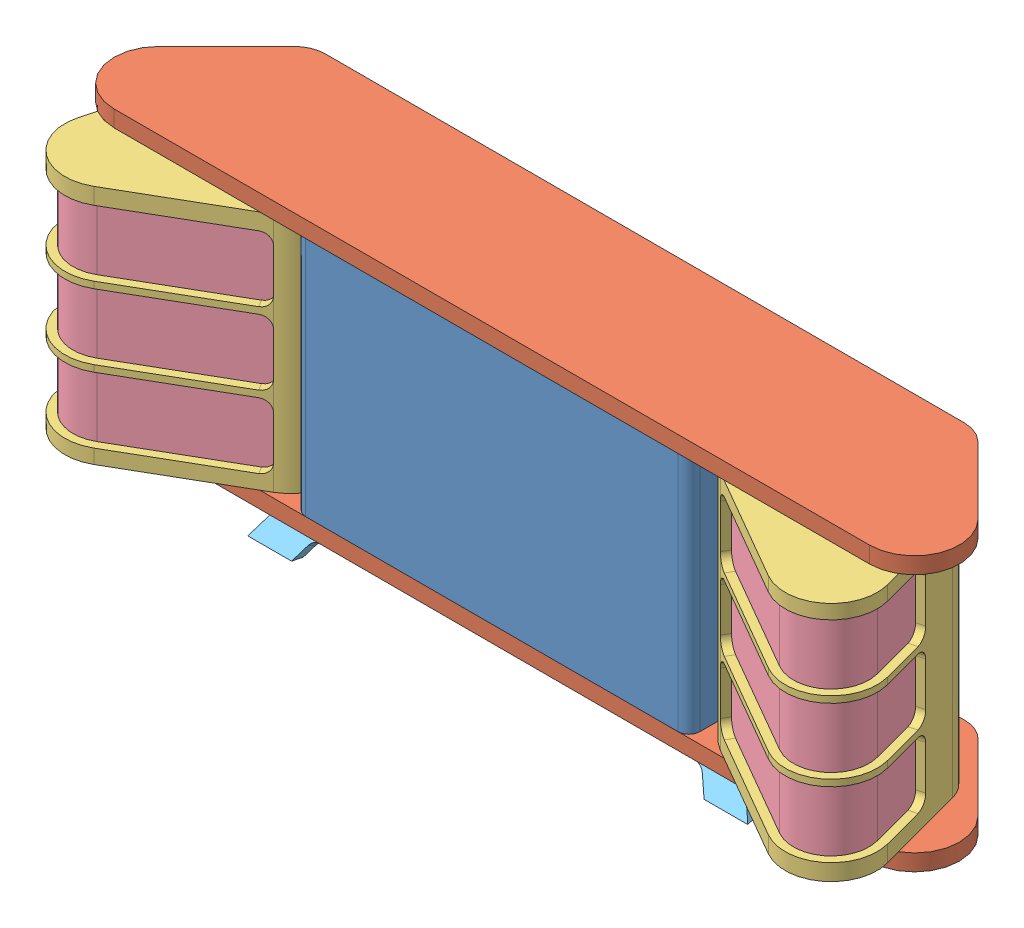
SolidWorks assembly Speakers installed, configuration Default. Lengths in mm.
Overall size (2104.56 725.08 567.1).
9 component instances, 5 part files, 24 mates.
Components (placement in the parent):
- Middle-1: Middle [Default] at (409.9999 227.4076 645.5134) size (914.4 558.8 355.6)
- top bottom-1: top bottom [Default] at (352.252 227.4076 660.7734) x (-1 0 0) z (0 0 1) size (1960.6 38.1 355.6)
- top bottom-2: top bottom [Default] at (467.7478 786.2076 660.7734) size (1960.6 38.1 355.6)
- speaker-1: speaker [Default] at (-265.4552 227.4076 843.7979) x (0.866025 0 -0.5) z (0.5 0 0.866025) size (518.28 558.8 355.6)
- insert-1: insert [Default] at (-295.2137 259.1576 744.9506) x (0.866025 0 -0.5) z (0.5 0 0.866025) size (480.18 508 317.5)
- speaker-2: speaker [Default] at (1085.455 786.2076 843.7979) x (-0.866025 0 -0.5) z (-0.5 0 0.866025) size (518.28 558.8 355.6)
- insert-2: insert [Default] at (1156.18 259.1576 768.6026) x (0.866025 0 0.5) z (-0.5 0 0.866025) size (480.18 508 317.5)
- feet-1: feet [Default] at (409.9999 198.1951 528.3717) x (1 0 0) z (0 -0.457029 0.889452) size (1159.95 101.27 19.05)
- feet-2: feet [Default] at (409.9999 198.1951 763.1915) x (-1 0 0) z (0 -0.457029 -0.889452) size (1159.95 101.27 19.05)
Mates (geometry in assembly coordinates):
- Coincident1: coincident anti-aligned: plane of Middle-1 through (409.9999 786.2076 645.5134) normal (0 1 0); plane of top bottom-2 through (-331.4645 786.2076 541.3734) normal (0 -1 0)
- Coincident2: coincident aligned: plane of Middle-1 through (-47.2001 786.2076 823.3134) normal (0 0 1); plane of top bottom-2 through (1280.027 824.3076 823.3134) normal (0 0 1)
- Coincident3: coincident aligned: plane of Middle-1 through (-47.2001 786.2076 823.3134) normal (0 0 1); plane of top bottom-1 through (-460.0272 189.3076 823.3134) normal (0 0 1)
- Coincident4: coincident anti-aligned: plane of Middle-1 through (409.9999 227.4076 645.5134) normal (0 -1 0); plane of top bottom-1 through (1151.4644 227.4076 541.3734) normal (0 1 0)
- Coincident5: coincident aligned: plane of top bottom-1 through (1355.4612 189.3076 641.1993) normal (0.707107 0 -0.707107); plane of top bottom-2 through (1359.7972 824.3076 645.5353) normal (0.707107 0 -0.707107)
- Width1: width anti-aligned: plane of top bottom-2 through (1359.7972 824.3076 645.5353) normal (0.707107 0 -0.707107); plane of top bottom-2 through (-535.4613 824.3076 641.1993) normal (-0.707107 0 -0.707107); plane of Middle-1 through (-47.2001 786.2076 823.3134) normal (-1 0 0); plane of Middle-1 through (867.1999 786.2076 823.3134) normal (1 0 0)
- Concentric1: concentric anti-aligned: cylinder of top bottom-2 through (-161.3593 798.9076 719.1734) axis (0 -1 0) radius 12.7; cylinder of speaker-1 through (-161.3593 227.4076 719.1734) axis (0 1 0) radius 12.7
- Concentric2: concentric aligned: cylinder of top bottom-1 through (-161.3593 214.7076 719.1734) axis (0 1 0) radius 12.7; cylinder of speaker-1 through (-161.3593 227.4076 719.1734) axis (0 1 0) radius 12.7
- Coincident6: coincident anti-aligned: plane of top bottom-1 through (1151.4644 227.4076 541.3734) normal (0 1 0); plane of speaker-1 through (-265.4552 227.4076 843.7979) normal (0 -1 0)
- Coincident7: coincident anti-aligned: plane of speaker-1 through (124.7509 227.4076 655.174) normal (-0.5 0 -0.866025); plane of insert-1 through (-381.6161 767.1576 947.5252) normal (0.5 0 0.866025)
- Coincident8: coincident anti-aligned: plane of speaker-1 through (-265.4552 767.1576 843.7979) normal (0 -1 0); plane of insert-1 through (-359.969 767.1576 634.4009) normal (0 1 0)
- Coincident9: coincident anti-aligned: plane of speaker-1 through (-426.6594 786.2076 537.6432) normal (0.965926 0 0.258819); plane of insert-1 through (-454.7441 767.1576 642.4566) normal (-0.965926 0 -0.258819)
- Coincident10: coincident anti-aligned: plane of top bottom-2 through (-331.4645 786.2076 541.3734) normal (0 -1 0); plane of speaker-2 through (1075.8406 786.2076 851.2358) normal (0 1 0)
- Concentric3: concentric aligned: cylinder of top bottom-2 through (981.3591 798.9076 719.1734) axis (0 -1 0) radius 12.7; cylinder of speaker-2 through (981.3591 786.2076 719.1734) axis (0 -1 0) radius 12.7
- Coincident11: coincident anti-aligned: plane of speaker-2 through (700.8382 786.2076 633.9503) normal (0.563384 0 -0.826195); plane of insert-2 through (931.9898 767.1576 791.5729) normal (-0.563384 0 0.826195)
- Coincident12: coincident anti-aligned: plane of speaker-2 through (1075.8406 767.1576 851.2358) normal (0 -1 0); plane of insert-2 through (1223.5063 767.1576 675.2393) normal (0 1 0)
- Coincident13: coincident anti-aligned: plane of speaker-2 through (1259.4957 227.4076 557.9982) normal (-0.982581 0 0.185836); plane of insert-2 through (1319.3894 767.1576 874.6778) normal (0.982581 0 -0.185836)
- Coincident14: coincident anti-aligned: plane of top bottom-1 through (1151.4644 189.3076 541.3734) normal (0 -1 0); plane of feet-1 through (-169.9754 189.3076 481.995) normal (0 1 0)
- Width2: width anti-aligned: plane of feet-1 through (940.1336 177.9796 539.402) normal (0.871403 0.436336 0.224204); plane of feet-1 through (-120.1337 177.9796 539.402) normal (-0.871403 0.436336 0.224204); plane of top bottom-1 through (-539.7974 189.3076 645.5353) normal (-0.707107 0 -0.707107); plane of top bottom-1 through (1355.4612 189.3076 641.1993) normal (0.707107 0 -0.707107)
- Coincident15: coincident anti-aligned: plane of top bottom-1 through (1151.4644 189.3076 541.3734) normal (0 -1 0); plane of feet-2 through (989.9752 189.3076 809.5681) normal (0 1 0)
- Parallel2: parallel: plane of top bottom-1 through (-460.0272 189.3076 823.3134) normal (0 0 1); line of feet-2 through (938.1929 189.3076 767.7581) axis (-1 0 0)
- Width3: width anti-aligned: plane of top bottom-1 through (1355.4612 189.3076 641.1993) normal (0.707107 0 -0.707107); plane of top bottom-1 through (-539.7974 189.3076 645.5353) normal (-0.707107 0 -0.707107); plane of feet-2 through (-120.1337 177.9796 752.1612) normal (-0.871403 0.436336 -0.224204); plane of feet-2 through (940.1336 177.9796 752.1612) normal (0.871403 0.436336 -0.224204)
- Angle1: planar angle = 0.523599 rad aligned: plane of top bottom-2 through (1280.027 824.3076 823.3134) normal (0 0 1); plane of speaker-1 through (134.2759 227.4076 671.6718) normal (0.5 0 0.866025)
- Angle2: planar angle = 0.523599 rad aligned: plane of top bottom-2 through (1280.027 824.3076 823.3134) normal (0 0 1); plane of speaker-2 through (685.724 786.2076 671.6718) normal (-0.5 0 0.866025)
